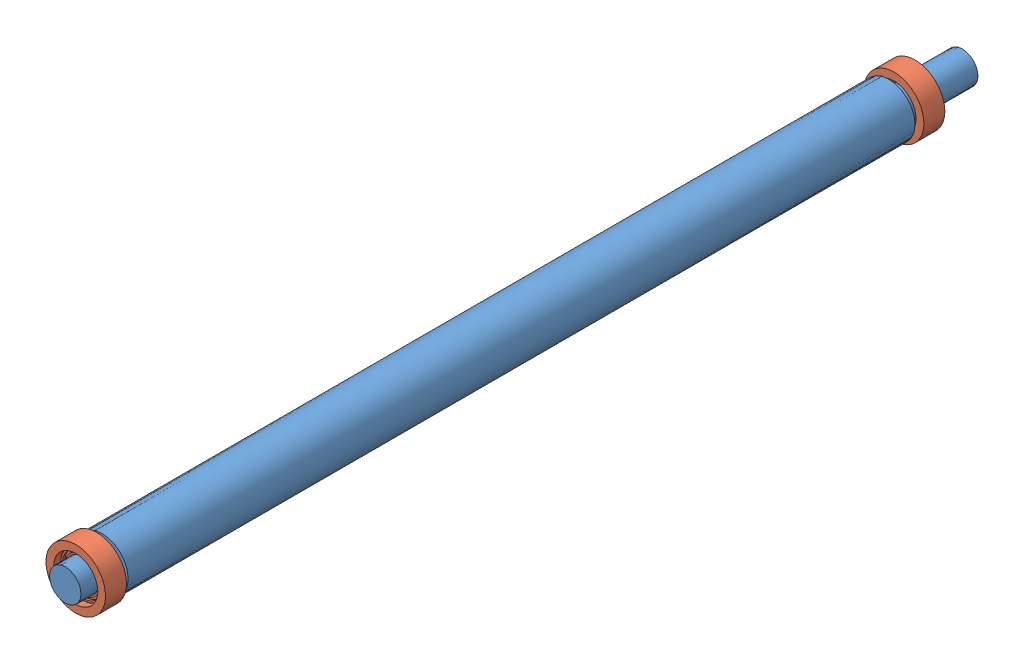
SolidWorks assembly Assem5, configuration Default. Lengths in mm.
Overall size (56.7 56.7 855).
3 component instances, 2 part files, 4 mates.
Components (placement in the parent):
- feed roller-1: feed roller [Default] at origin size (50 50 855)
- Feed roller Steel frame w bearing-1: Feed roller Steel frame w bearing [Default] at (0 0 755) size (56.7 56.7 20)
- Feed roller Steel frame w bearing-2: Feed roller Steel frame w bearing [Default] at (0 0 -25) size (56.7 56.7 20)
Mates (geometry in assembly coordinates):
- Concentric2: concentric: circle of feed roller-1; circle of Feed roller Steel frame w bearing-1
- Distance2: distance = 5 mm: plane of Feed roller Steel frame w bearing-1 through (0 0 755) normal (0 0 -1); plane of feed roller-1 through (0 0 750) normal (0 0 1)
- Concentric3: concentric: circle of feed roller-1; circle of Feed roller Steel frame w bearing-2
- Distance3: distance = 5 mm: plane of Feed roller Steel frame w bearing-2 through (0 0 -5) normal (0 0 1); plane of feed roller-1 through (0 0 0) normal (0 0 -1)
